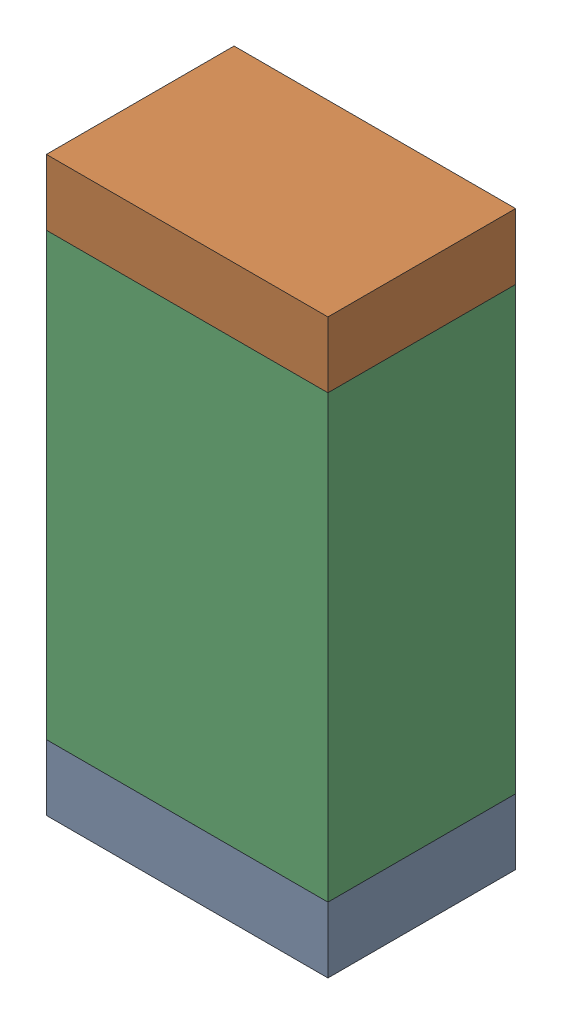
SolidWorks assembly C1, configuration Default. Lengths in mm.
Overall size (0.76 1.55 0.51).
6 component instances, 2 part files, 0 mates.
Components (placement in the parent):
- 822501776-1: 822501776 [Default] at (29.9203 8.0954 0) size (0.76 0.18 0.51)
  - Extruded_3-1: Extruded_3 [Default] at origin size (0.76 0.18 0.51)
- 822501776-2: 822501776 [Default] at (29.9203 9.4669 0) size (0.76 0.18 0.51)
  - Extruded_3-1: Extruded_3 [Default] at origin size (0.76 0.18 0.51)
- 822501912-1: 822501912 [Default] at (29.9203 8.7811 0) size (0.76 1.19 0.51)
  - Extruded_4-1: Extruded_4 [Default] at origin size (0.76 1.19 0.51)
